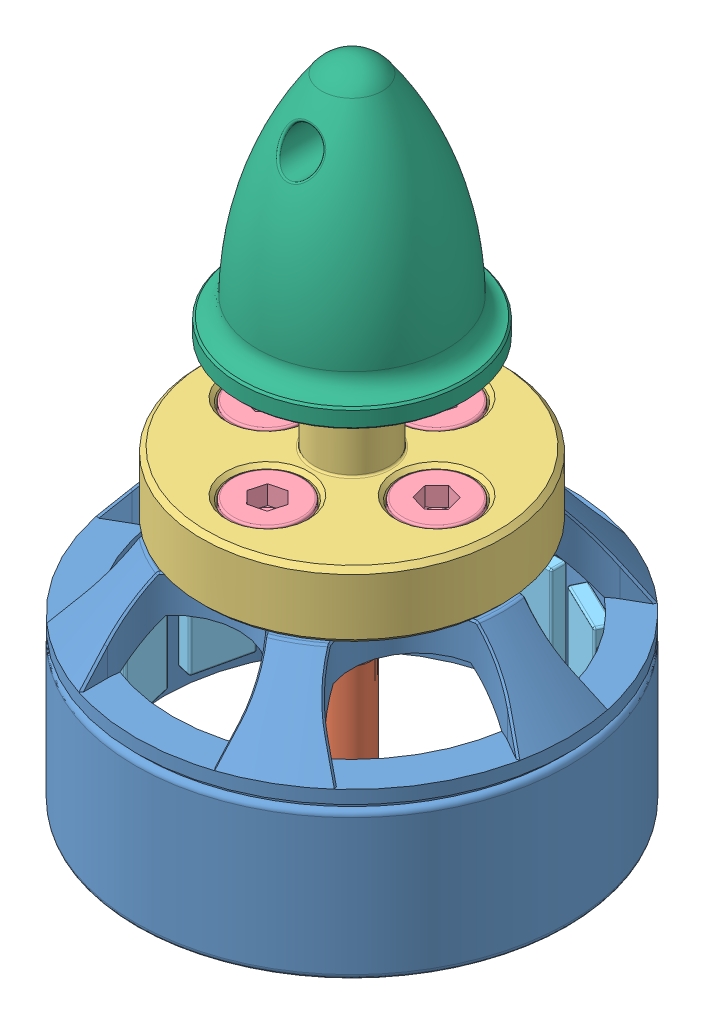
SolidWorks assembly Rotor Assembly, configuration Défaut. Lengths in mm.
Overall size (23 41.5 23).
22 component instances, 6 part files, 15 mates.
Components (placement in the parent):
- Front housing-1: Front housing [Défaut] x (0 0 1) z (0 -1 0) size (23 23 13)
- Shaft-1: Shaft [Défaut] at (0 3.5 0) x (1 0 0) z (0 -1 0) size (2 2 23.5)
- Prop Adapter-2: Prop Adapter [Défaut] x (1 0 0) z (0 1 0) size (16 16 14.5)
- socket head cap screw_iso-10: socket head cap screw_iso [ISO 4762 M2 x 4 --- 4S] at (0 3.4 -4.5) x (0 -1 0) z (-0.716616 0 0.697467) size (6 3.8 3.8)
- Magnets-1: Magnets [Défaut] at (0 -9 9.1) x (1 0 0) z (0 -1 0) size (3 0.85 6)
- Magnets-2: Magnets [Défaut] at (-3.9483 -9 8.1988) x (0.900969 0 0.433884) z (0 -1 0) size (3 0.85 6)
- Magnets-3: Magnets [Défaut] at (-7.1147 -9 5.6738) x (0.62349 0 0.781831) z (0 -1 0) size (3 0.85 6)
- Magnets-4: Magnets [Défaut] at (-8.8718 -9 2.0249) x (0.222521 0 0.974928) z (0 -1 0) size (3 0.85 6)
- Magnets-5: Magnets [Défaut] at (-8.8718 -9 -2.0249) x (-0.222521 0 0.974928) z (0 -1 0) size (3 0.85 6)
- Magnets-6: Magnets [Défaut] at (-7.1147 -9 -5.6738) x (-0.62349 0 0.781831) z (0 -1 0) size (3 0.85 6)
- Magnets-7: Magnets [Défaut] at (-3.9483 -9 -8.1988) x (-0.900969 0 0.433884) z (0 -1 0) size (3 0.85 6)
- Magnets-8: Magnets [Défaut] at (0 -9 -9.1) x (-1 0 0) z (0 -1 0) size (3 0.85 6)
- Magnets-9: Magnets [Défaut] at (3.9483 -9 -8.1988) x (-0.900969 0 -0.433884) z (0 -1 0) size (3 0.85 6)
- Magnets-10: Magnets [Défaut] at (7.1147 -9 -5.6738) x (-0.62349 0 -0.781831) z (0 -1 0) size (3 0.85 6)
- Magnets-11: Magnets [Défaut] at (8.8718 -9 -2.0249) x (-0.222521 0 -0.974928) z (0 -1 0) size (3 0.85 6)
- Magnets-12: Magnets [Défaut] at (8.8718 -9 2.0249) x (0.222521 0 -0.974928) z (0 -1 0) size (3 0.85 6)
- Magnets-13: Magnets [Défaut] at (7.1147 -9 5.6738) x (0.62349 0 -0.781831) z (0 -1 0) size (3 0.85 6)
- Magnets-14: Magnets [Défaut] at (3.9483 -9 8.1988) x (0.900969 0 -0.433884) z (0 -1 0) size (3 0.85 6)
- socket head cap screw_iso-13: socket head cap screw_iso [ISO 4762 M2 x 4 --- 4S] at (4.5 3.4 0) x (0 -1 0) z (-0.697467 0 -0.716616) size (6 3.8 3.8)
- socket head cap screw_iso-14: socket head cap screw_iso [ISO 4762 M2 x 4 --- 4S] at (0 3.4 4.5) x (0 -1 0) z (0.716616 0 -0.697467) size (6 3.8 3.8)
- socket head cap screw_iso-15: socket head cap screw_iso [ISO 4762 M2 x 4 --- 4S] at (-4.5 3.4 0) x (0 -1 0) z (0.697467 0 0.716616) size (6 3.8 3.8)
- Propeller Cone-1: Propeller Cone [Défaut] at (0 8.5 0) x (0.017814 0 0.999841) z (0 -1 0) size (12 12 13)
Mates (geometry in assembly coordinates):
- Coïncidente1: coincident: plane of Front housing-1 through (0 0 0) normal (0 0 1); plane of assembly through (0 0 0) normal (0 0 1)
- Coïncidente2: coincident: plane of Front housing-1 through (0 0 0) normal (0 -1 0); plane of assembly through (0 0 0) normal (0 1 0)
- Coïncidente3: coincident anti-aligned: plane of Front housing-1 through (0 0 0) normal (-1 0 0); plane of assembly through (0 0 0) normal (1 0 0)
- Coaxiale1: concentric anti-aligned: cylinder of Front housing-1 through (0 -13.001 0) axis (0 1 0) radius 1; cylinder of Shaft-1 through (0 -20 0) axis (0 -1 0) radius 1
- Distance1: distance = 3.5 mm aligned: plane of Shaft-1 through (0 3.5 0) normal (0 1 0); plane of Front housing-1 through (0 0 0) normal (0 1 0)
- Coaxiale2: concentric aligned: cylinder of Shaft-1 through (0 -20 0) axis (0 -1 0) radius 1; cylinder of Prop Adapter-2 through (0 3.5 0) axis (0 -1 0) radius 1
- Coaxiale3: concentric aligned: cylinder of Front housing-1 through (0 0 4.5) axis (0 1 0) radius 0.8; cylinder of Prop Adapter-2 through (0 3.5 4.5) axis (0 1 0) radius 1.05
- Coïncidente5: coincident anti-aligned: plane of Front housing-1 through (0 0 0) normal (0 1 0); plane of Prop Adapter-2 through (0 0 0) normal (0 -1 0)
- Coaxiale9: concentric aligned: cylinder of Prop Adapter-2 through (0 3.5 -4.5) axis (0 1 0) radius 2; cylinder of socket head cap screw_iso-10 through (0 35.15 -4.5) axis (0 1 0) radius 1.9
- Coïncidente11: coincident anti-aligned: plane of Prop Adapter-2 through (1.05 1.4 -4.5) normal (0 1 0); plane of socket head cap screw_iso-10 through (1.3252 1.4 -3.1384) normal (0 -1 0)
- Symétrique1: symmetric aligned: plane of Magnets-1 through (-1.5 -12 9.95) normal (-1 0 0); plane of Magnets-1 through (1.5 -12 9.95) normal (1 0 0); plane of assembly through (0 0 0) normal (1 0 0)
- Distance2: distance = 1 mm aligned: plane of Magnets-1 through (1.5 -12 9.95) normal (0 -1 0); plane of Front housing-1 through (-11.5 -13 0) normal (0 -1 0)
- Distance3: distance = 9.1 mm anti-aligned: plane of Magnets-1 through (0 -9 9.1) normal (0 0 -1); plane of assembly through (0 0 0) normal (0 0 1)
- Coaxiale10: concentric anti-aligned: cylinder of Prop Adapter-2 through (0 1000 0) axis (0 1 0) radius 2; cylinder of Propeller Cone-1 through (0 8.5 0) axis (0 -1 0) radius 1.65
- Distance4: distance = 5 mm anti-aligned: plane of Propeller Cone-1 through (0 8.5 0) normal (0 -1 0); plane of Prop Adapter-2 through (0 3.5 -8) normal (0 1 0)
